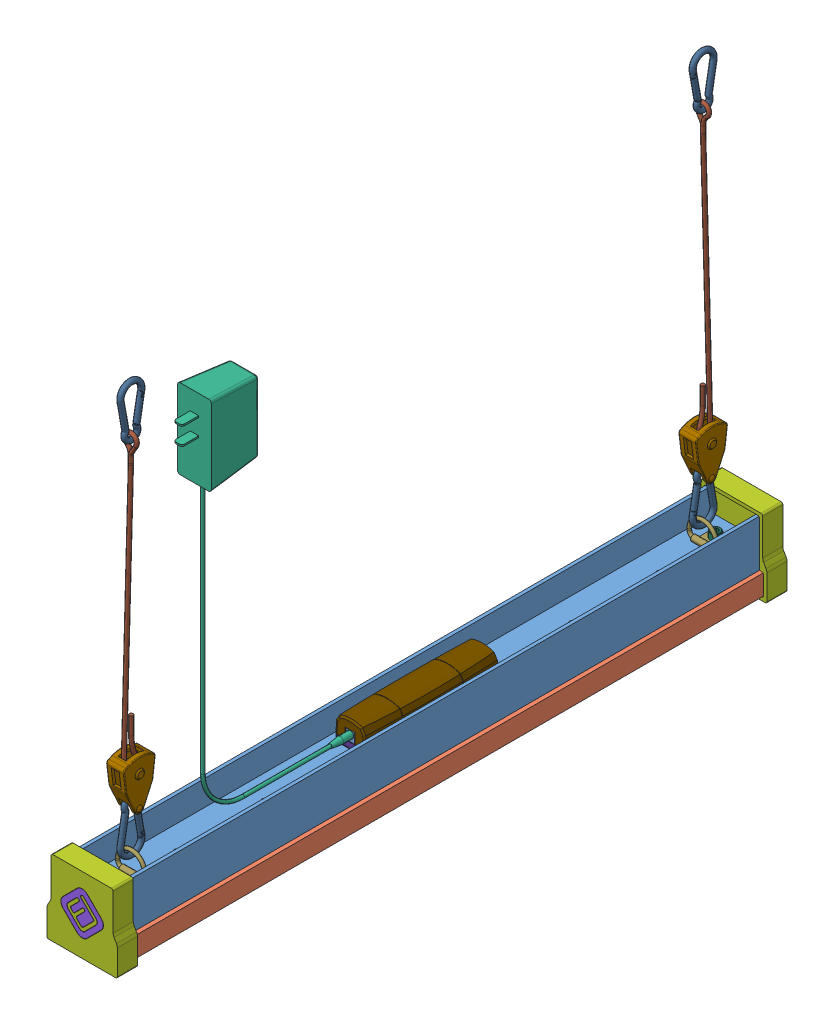
SolidWorks assembly ASM1001, configuration Default. Lengths in mm.
Overall size (66.61 452.68 637.86).
47 component instances, 20 part files, 61 mates.
Components (placement in the parent):
- EXT1003-1: EXT1003 [Default] at origin size (50.8 50.8 606.42)
- EXT1005-5: EXT1005 [Default] at (-23.8125 -28.575 0) size (11.11 19.05 606.42)
- LEN1001-1: LEN1001 [Default] at (0 -31.75 0) size (46.23 1.52 605.03)
- PCB1002-1: PCB1002 [Default] at (-25.4 -1.5875 -304.8) x (0 0 1) z (0 -1 0) size (551.18 12.75 6.6)
- REF1004-1: REF1004 [Default] at (0 -3.1875 0) size (47.75 27.7 590.55)
- PWR1003-1: PWR1003 [Default] at (0 14.7107 63.19) x (0 0 -1) z (1 0 0) size (169.87 358.78 32)
- COV1001-1: COV1001 [Default] at (0 0 303.2125) size (66.61 71.37 19.05)
- COV1002-1: COV1002 [Default] at origin size (39.93 39.94 1.54)
- MIS1003-1: MIS1003 [Default] at (0 61.7521 271.018) x (0 0 -1) z (1 0 0) size (29.94 392.99 19.3)
  - MIS1003-2-1: MIS1003-2 [Default] at origin size (29.94 46.91 19.3)
  - MIS1003-3-1: MIS1003-3 [Default] at (0 -31.75 0) size (24.69 52.63 4.88)
  - MIS1003-3-2: MIS1003-3 [Default] at (0 336.55 0) x (1 0 0) z (0 0 -1) size (24.69 52.63 4.88)
  - MIS1003-1-1: MIS1003-1 [Default] at origin size (17.27 286.13 14.73)
- BKT1002-1: BKT1002 [Default] at (0 4.7625 270.6687) size (28.57 23.81 23.43)
- MIS1001-1: MIS1001 [Catch] at (0 -12.5095 310.8325) x (1 0 0) z (0 0 -1) size (50.8 17.8 13.33)
- MIS1001-5: MIS1001 [Strike] at (0 -11.1125 310.8325) x (1 0 0) z (0 0 -1) size (28.57 19.05 18.54)
- FST1001-13: FST1001 [Default] at (0 2.7561 228.6) x (0 0 -1) z (0 -1 0) size (5.56 5.56 8.66)
- FST1001-17: FST1001 [Default] at (0 2.7561 146.05) x (0 0 1) z (0 -1 0) size (5.56 5.56 8.66)
- FST1001-20: FST1001 [Default] at (-9.525 3.81 288.544) x (0 0 -1) z (0 -1 0) size (5.56 5.56 8.66)
- FST1001-29: FST1001 [Default] at (9.525 3.81 288.544) x (0 0 -1) z (0 -1 0) size (5.56 5.56 8.66)
- FST1002-1: FST1002 [Default] at (0 -3.236 282.575) x (0 0 1) z (0 -1 0) size (9.53 9.53 13.37)
- FST1004-1: FST1004 [Default] at (-18.796 -12.5095 306.8637) x (1 0 0) z (0 0 -1) size (5.56 5.56 14.1)
- EXT1005-7: EXT1005 [Default] at (23.8125 -28.575 0) x (-1 0 0) z (0 0 -1) size (11.11 19.05 606.42)
- FST1004-6: FST1004 [Default] at (18.796 -12.5095 306.8637) x (1 0 0) z (0 0 -1) size (5.56 5.56 14.1)
- FST1004-7: FST1004 [Default] at (-18.796 -12.5095 -306.8637) x (-1 0 0) z (0 0 1) size (5.56 5.56 14.1)
- FST1004-8: FST1004 [Default] at (18.796 -12.5095 -306.8637) x (-1 0 0) z (0 0 1) size (5.56 5.56 14.1)
- FST1002-4: FST1002 [Default] at (0 -3.236 -282.575) x (0 0 -1) z (0 -1 0) size (9.53 9.53 13.37)
- FST1001-30: FST1001 [Default] at (-9.525 3.81 -288.544) x (0 0 1) z (0 -1 0) size (5.56 5.56 8.66)
- FST1001-31: FST1001 [Default] at (9.525 3.81 -288.544) x (0 0 1) z (0 -1 0) size (5.56 5.56 8.66)
- FST1001-32: FST1001 [Default] at (0 2.7561 -146.05) x (0 0 -1) z (0 -1 0) size (5.56 5.56 8.66)
- FST1001-33: FST1001 [Default] at (0 2.7561 -228.6) x (0 0 1) z (0 -1 0) size (5.56 5.56 8.66)
- MIS1001-7: MIS1001 [Strike] at (0 -11.1125 -310.8325) x (-1 0 0) z (0 0 1) size (28.57 19.05 18.54)
- MIS1001-8: MIS1001 [Catch] at (0 -12.5095 -310.8325) x (-1 0 0) z (0 0 1) size (50.8 17.8 13.33)
- BKT1002-3: BKT1002 [Default] at (0 4.7625 -270.6687) x (-1 0 0) z (0 0 -1) size (28.57 23.81 23.43)
- MIS1003-3: MIS1003 [Default] at (0 61.7521 -271.018) x (0 0 1) z (-1 0 0) size (29.94 392.99 19.3)
  - MIS1003-2-1: MIS1003-2 [Default] at origin size (29.94 46.91 19.3)
  - MIS1003-3-1: MIS1003-3 [Default] at (0 -31.75 0) size (24.69 52.63 4.88)
  - MIS1003-3-2: MIS1003-3 [Default] at (0 336.55 0) x (1 0 0) z (0 0 -1) size (24.69 52.63 4.88)
  - MIS1003-1-1: MIS1003-1 [Default] at origin size (17.27 286.13 14.73)
- COV1001-4: COV1001 [Default] at (0 0 -303.2125) x (-1 0 0) z (0 0 -1) size (66.61 71.37 19.05)
- COV1002-4: COV1002 [Default] x (-1 0 0) z (0 0 -1) size (39.93 39.94 1.54)
- HSG1001-2: HSG1001 [Default] at (0 8.4455 0) x (0 0 1) z (-1 0 0) size (127.04 25.41 31.78)
  - HSG1001-1-1: HSG1001-1 [Default] x (1 0 0) z (0 1 0) size (127.04 31.78 6.96)
  - HSG1001-2-1: HSG1001-2 [Default] x (1 0 0) z (0 1 0) size (127.03 31.72 19.32)
- PCB1003-1: PCB1003 [Default] at (0 6.8707 0) x (0 0 1) z (0 1 0) size (124.15 25.4 14.67)
- FST1003-2: FST1003 [Default] at (10.16 6.35 58.547) x (1 0 0) z (0 -1 0) size (5.56 5.56 19.81)
- FST1003-3: FST1003 [Default] at (-10.16 6.35 -58.547) x (-1 0 0) z (0 -1 0) size (5.56 5.56 19.81)
Mates (geometry in assembly coordinates):
- Coincident1: coincident aligned: plane of LEN1001-1 through (0 -31.75 0) normal (1 0 0); plane of assembly through (0 0 0) normal (1 0 0)
- Coincident2: coincident aligned: plane of LEN1001-1 through (0 -31.75 0) normal (0 0 1); plane of assembly through (0 0 0) normal (0 0 1)
- Coincident47: coincident anti-aligned: plane of PCB1002-1; plane of assembly through (0 0 0) normal (0 0 1)
- Coincident48: coordinate: point of ?
- Coincident49: coincident anti-aligned: plane of EXT1003-1 through (-22.225 -1.5875 303.2125) normal (0 -1 0); plane of PCB1002-1 through (-6.35 -1.5875 -275.59) normal (0 1 0)
- Coincident52: coincident aligned: plane of EXT1005-5 through (-23.8125 -28.575 0) normal (0 0 1); plane of assembly through (0 0 0) normal (0 0 1)
- Coincident69: coincident aligned: plane of PWR1003-1 through (0 14.7107 63.19) normal (1 0 0); plane of assembly through (0 0 0) normal (1 0 0)
- Coincident70: coincident anti-aligned: plane of EXT1003-1 through (-25.4 -25.4 303.2125) normal (0 -1 0); plane of EXT1005-5 through (-25.4 -25.4 -303.2125) normal (0 1 0)
- Coincident71: coincident anti-aligned: plane of EXT1003-1 through (-25.4 -25.4 303.2125) normal (-1 0 0); plane of EXT1005-5 through (-25.4 -25.4 -303.2125) normal (1 0 0)
- Coincident88: coincident anti-aligned: plane of PCB1002-1; plane of assembly through (0 0 0) normal (1 0 0)
- Coincident89: coincident aligned: plane of ? through (0 61.7521 271.018) normal (1 0 0); plane of assembly through (0 0 0) normal (1 0 0)
- Distance4: distance = 271.018 mm anti-aligned: plane of ? through (0 61.7521 271.018) normal (0 0 -1); plane of assembly through (0 0 0) normal (0 0 1)
- Concentric14: concentric anti-aligned: cylinder of EXT1003-1 through (0 1.5875 282.575) axis (0 1 0) radius 2.5527; cylinder of BKT1002-1 through (0 25.4 282.575) axis (0 -1 0) radius 3.302
- Coincident90: coincident anti-aligned: plane of EXT1003-1 through (-22.225 1.5875 303.2125) normal (0 1 0); plane of BKT1002-1 through (8.7312 1.5875 291.3062) normal (0 -1 0)
- Coincident91: coincident aligned: plane of BKT1002-1 through (0 4.7625 270.6687) normal (1 0 0); plane of assembly through (0 0 0) normal (1 0 0)
- Concentric15: concentric anti-aligned: cylinder of EXT1003-1 through (0 1.5875 282.575) axis (0 1 0) radius 2.5527; cylinder of FST1002-1 through (0 3.114 282.575) axis (0 -1 0) radius 3.175
- Coincident92: coincident anti-aligned: plane of BKT1002-1 through (8.7312 3.114 291.3062) normal (0 1 0); plane of FST1002-1 through (0 3.114 282.575) normal (0 -1 0)
- Concentric16: concentric anti-aligned: cylinder of FST1001-17 through (0 2.7561 146.05) axis (0 1 0) radius 2.7813; cylinder of EXT1003-1 through (0 25.4 146.05) axis (0 -1 0) radius 1.0922
- Concentric17: concentric anti-aligned: cylinder of FST1001-13 through (0 2.7561 228.6) axis (0 1 0) radius 2.7813; cylinder of EXT1003-1 through (0 25.4 228.6) axis (0 -1 0) radius 1.0922
- Distance6: distance = 2.032 mm anti-aligned: plane of EXT1003-1 through (-22.225 -1.5875 303.2125) normal (0 -1 0); plane of MIS1001-1 through (25.4 -3.6195 306.8637) normal (0 1 0)
- Coincident96: coincident aligned: plane of MIS1001-1; plane of assembly through (0 0 0) normal (1 0 0)
- Distance5: distance = 7.62 mm aligned: plane of MIS1001-1 through (-25.4 -3.6195 310.8325) normal (0 0 1); plane of EXT1003-1 through (0 0 303.2125) normal (0 0 1)
- Coincident98: coincident anti-aligned: plane of EXT1003-1 through (-22.225 -1.5875 303.2125) normal (0 -1 0); plane of MIS1001-5 through (-14.2875 -1.5875 294.9575) normal (0 1 0)
- Coincident99: coincident aligned: plane of MIS1001-5; plane of assembly through (0 0 0) normal (1 0 0)
- Coincident101: coincident anti-aligned: plane of MIS1001-1 through (8.255 -5.6515 297.4975) normal (0 0 -1); plane of MIS1001-5 through (-14.2875 -20.6375 297.4975) normal (0 0 1)
- Concentric19: concentric aligned: cylinder of EXT1003-1 through (-9.525 -25.4 288.544) axis (0 1 0) radius 1.0922; cylinder of FST1001-20 through (-9.525 3.81 288.544) axis (0 1 0) radius 2.7813
- Coincident103: coincident anti-aligned: plane of MIS1001-5 through (-14.2875 -2.54 294.9575) normal (0 -1 0); plane of FST1001-20 through (-9.525 -2.54 288.544) normal (0 1 0)
- Coincident104: coincident anti-aligned: plane of FST1001-13 through (0 -3.5939 228.6) normal (0 1 0); plane of REF1004-1 through (7.9375 -3.5939 295.275) normal (0 -1 0)
- Coincident105: coincident anti-aligned: plane of FST1001-17 through (0 -3.5939 146.05) normal (0 1 0); plane of REF1004-1 through (7.9375 -3.5939 295.275) normal (0 -1 0)
- Parallel1: parallel aligned: plane of FST1001-13; plane of assembly through (0 0 0) normal (1 0 0)
- Parallel2: parallel anti-aligned: plane of FST1002-1; plane of assembly through (0 0 0) normal (1 0 0)
- Parallel3: parallel anti-aligned: plane of FST1001-17; plane of assembly through (0 0 0) normal (1 0 0)
- Parallel4: parallel aligned: plane of FST1004-1; plane of assembly through (0 0 0) normal (1 0 0)
- Parallel5: parallel aligned: plane of FST1001-20; plane of assembly through (0 0 0) normal (1 0 0)
- Coincident111: coincident anti-aligned: plane of PCB1002-1 through (-6.35 -3.1875 -275.59) normal (0 -1 0); plane of REF1004-1 through (7.9375 -3.1875 295.275) normal (0 1 0)
- Coincident112: coincident aligned: plane of REF1004-1 through (0 -3.1875 0) normal (0 0 1); plane of assembly through (0 0 0) normal (0 0 1)
- Coincident113: coincident aligned: plane of REF1004-1 through (0 -3.1875 0) normal (1 0 0); plane of assembly through (0 0 0) normal (1 0 0)
- Distance7: distance = 61.7521 mm aligned: plane of ?; plane of assembly through (0 0 0) normal (0 1 0)
- Coincident115: coincident aligned: plane of COV1001-1 through (0 0 303.2125) normal (0 1 0); plane of assembly through (0 0 0) normal (0 1 0)
- Coincident116: coincident aligned: plane of COV1001-1 through (0 0 303.2125) normal (1 0 0); plane of assembly through (0 0 0) normal (1 0 0)
- Coincident117: coincident anti-aligned: plane of EXT1003-1 through (0 0 303.2125) normal (0 0 1); plane of COV1001-1 through (0 0 303.2125) normal (0 0 -1)
- Width1: width anti-aligned: plane of EXT1005-5 through (-18.2563 -33.3375 -303.2125) normal (0 1 0); plane of EXT1005-5 through (-18.2563 -30.1625 -303.2125) normal (0 -1 0); plane of LEN1001-1 through (-23.114 -32.512 302.514) normal (0 -1 0); plane of LEN1001-1 through (-23.114 -30.988 302.514) normal (0 1 0)
- Concentric20: concentric aligned: cylinder of MIS1001-1 through (-18.796 -12.5095 306.8637) axis (0 0 1) radius 2.032; cylinder of FST1004-1 through (-18.796 -12.5095 307.5252) axis (0 0 1) radius 1.4224
- Coincident118: coincident anti-aligned: plane of MIS1001-1 through (-25.4 -3.6195 306.8637) normal (0 0 -1); plane of FST1004-1 through (-18.796 -12.5095 306.8637) normal (0 0 1)
- Parallel6: parallel aligned: plane of FST1004-6; plane of assembly through (0 0 0) normal (1 0 0)
- Concentric21: concentric aligned: cylinder of MIS1001-1 through (18.796 -12.5095 306.8637) axis (0 0 1) radius 2.032; cylinder of FST1004-6 through (18.796 -12.5095 307.5252) axis (0 0 1) radius 1.4224
- Coincident120: coincident anti-aligned: plane of MIS1001-1 through (-25.4 -3.6195 306.8637) normal (0 0 -1); plane of FST1004-6 through (18.796 -12.5095 306.8637) normal (0 0 1)
- Parallel7: parallel aligned: plane of FST1001-29; plane of assembly through (0 0 0) normal (1 0 0)
- Concentric22: concentric anti-aligned: cylinder of EXT1003-1 through (9.525 -25.4 288.544) axis (0 1 0) radius 1.0922; cylinder of FST1001-29 through (9.525 3.81 288.544) axis (0 -1 0) radius 1.4224
- Coincident122: coincident anti-aligned: plane of MIS1001-5 through (-14.2875 -2.54 294.9575) normal (0 -1 0); plane of FST1001-29 through (9.525 -2.54 288.544) normal (0 1 0)
- Coincident123: coincident anti-aligned: plane of PCB1003-1 through (12.7 6.8707 0) normal (0 -1 0); plane of HSG1001-2/HSG1001-1-1 through (-11.8364 6.8707 21.7805) normal (0 1 0)
- Coincident124: coincident anti-aligned: plane of EXT1003-1 through (-22.225 1.5875 303.2125) normal (0 1 0); plane of ? through (-15.889 1.5875 -38.1127) normal (0 -1 0)
- Concentric23: concentric aligned: cylinder of PWR1003-1 through (0 14.7107 56.84) axis (0 0 1) radius 2.286; cylinder of PCB1003-1 through (0 14.7107 53.59) axis (0 0 1) radius 3.2
- Coincident125: coincident anti-aligned: plane of PCB1003-1 through (0 13.5607 63.19) normal (0 0 1); plane of PWR1003-1 through (0 14.7107 63.19) normal (0 0 -1)
- Coincident126: coincident anti-aligned: plane of HSG1001-2 through (0 8.4455 0) normal (-1 0 0); plane of assembly through (0 0 0) normal (1 0 0)
- Coincident127: coincident aligned: plane of HSG1001-2 through (0 8.4455 0) normal (0 0 1); plane of assembly through (0 0 0) normal (0 0 1)
- Coincident128: coincident anti-aligned: plane of HSG1001-2 through (0 8.4455 0) normal (-1 0 0); plane of PCB1003-1
- Coincident129: coincident aligned: plane of HSG1001-2 through (0 8.4455 0) normal (0 0 1); plane of PCB1003-1
- Concentric24: concentric aligned: cylinder of EXT1003-1 through (10.16 -25.4 58.547) axis (0 1 0) radius 1.7272; cylinder of FST1003-2 through (10.16 -3.6195 58.547) axis (0 1 0) radius 2.7813
- Coincident130: coincident anti-aligned: plane of EXT1003-1 through (-22.225 -1.5875 303.2125) normal (0 -1 0); plane of FST1003-2 through (10.16 -1.5875 58.547) normal (0 1 0)
- Parallel8: parallel aligned: plane of FST1003-2; plane of assembly through (0 0 0) normal (1 0 0)
